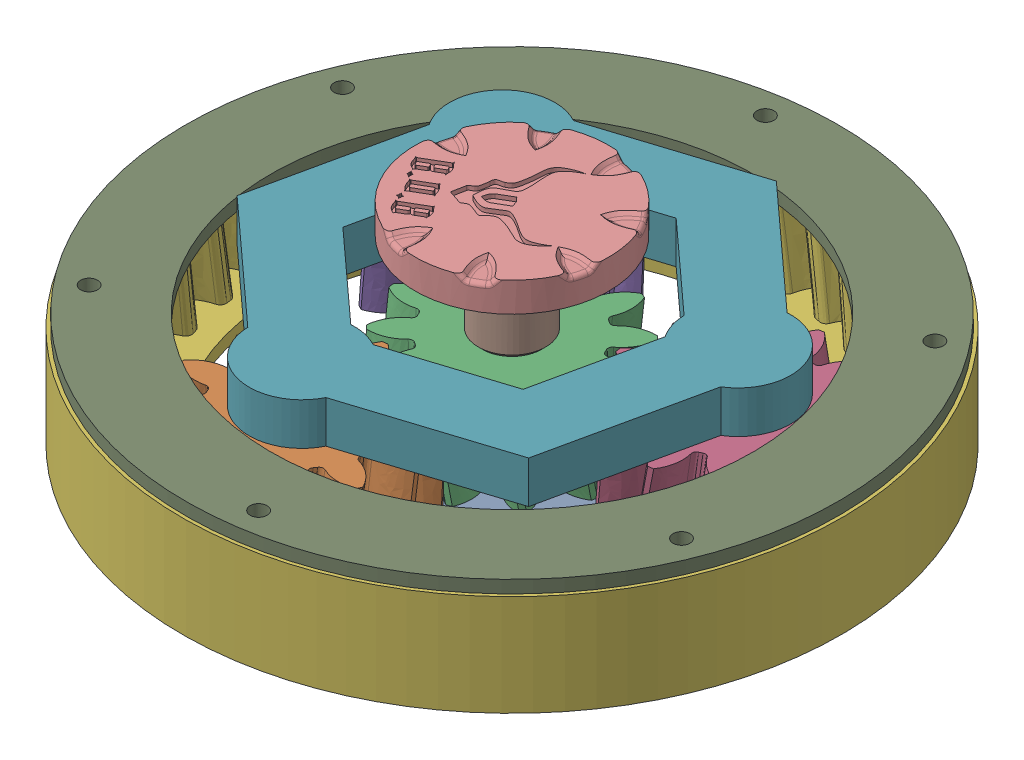
SolidWorks assembly planetary_module_prototype, configuration Default. Lengths in mm.
Overall size (177.94 57 177.94).
10 component instances, 8 part files, 27 mates.
Components (placement in the parent):
- Planet Carrier REV01-1: Planet Carrier REV01 [Default] at (53.0057 38.5104 215.4418) x (-0.977013 0 -0.213181) z (0 1 0) size (94.36 84.54 31)
- planet_helical-1: planet_helical [Default] at (43.976 53.5104 256.8251) x (0.343265 0 0.939239) z (-0.939239 0 0.343265) size (48.42 20.01 48.73)
- sun_helical-1: sun_helical [Default] at (53.0057 53.5104 215.4418) x (0.868502 0 0.495686) z (-0.495686 0 0.868502) size (48.42 20.01 48.73)
- planet_helical-2: planet_helical [Default] at (93.3596 53.5104 202.57) x (0.985013 0 0.172478) z (-0.172478 0 0.985013) size (48.42 20.01 48.73)
- planet_helical-3: planet_helical [Default] at (21.6816 53.5104 186.9302) x (0.641398 0 -0.767208) z (0.767208 0 0.641398) size (48.42 20.01 48.73)
- ring_helical-1: ring_helical [Default] at (53.0057 54.0104 215.4418) x (0.989106 0 -0.147208) z (0.147208 0 0.989106) size (156.59 24 156.59)
- Planet Cap REV01-1: Planet Cap REV01 [Default] at (53.0919 69.5104 215.0469) x (0.673126 0 -0.739528) z (0 1 0) size (98.36 107.21 19)
- Hand Crank Key REV01-1: Hand Crank Key REV01 [Default] at (53.0057 63.5104 215.4418) x (0.495686 0 -0.868502) z (-0.868502 0 -0.495686) size (18.48 32 16)
- ring_helical_cap-1: ring_helical_cap [Default] at (53.0057 64.5104 215.4418) x (0.989106 0 -0.147208) z (0.147208 0 0.989106) size (155 3 155)
- Hand Crank REV01-2: Hand Crank REV01 [Default] at (53.0057 63.5104 215.4418) x (0.504302 0 0.863527) z (0.863527 0 -0.504302) size (46 7 46)
Mates (geometry in assembly coordinates):
- Concentric1: concentric anti-aligned: cylinder of Planet Carrier REV01-1 through (21.6816 64.5104 186.9302) axis (0 -1 0) radius 9.75; cylinder of planet_helical-3 through (21.6816 43.5061 186.9302) axis (0 1 0) radius 10.1
- Coincident1: coincident anti-aligned: plane of Planet Carrier REV01-1 through (53.0057 43.5104 215.4418) normal (0 1 0); plane of planet_helical-3 through (21.6816 43.5104 186.9302) normal (0 -1 0)
- Concentric2: concentric anti-aligned: cylinder of Planet Carrier REV01-1 through (53.0057 84.0165 215.4418) axis (0 -1 0) radius 7.25; cylinder of sun_helical-1 through (53.0057 43.5061 215.4418) axis (0 1 0) radius 7.6
- Coincident2: coincident anti-aligned: plane of Planet Carrier REV01-1 through (53.0057 43.5104 215.4418) normal (0 1 0); plane of sun_helical-1 through (53.0057 43.5104 215.4418) normal (0 -1 0)
- Concentric3: concentric anti-aligned: cylinder of Planet Carrier REV01-1 through (43.976 64.5104 256.8251) axis (0 -1 0) radius 9.75; cylinder of planet_helical-1 through (43.976 43.5061 256.8251) axis (0 1 0) radius 10.1
- Coincident3: coincident anti-aligned: plane of Planet Carrier REV01-1 through (53.0057 43.5104 215.4418) normal (0 1 0); plane of planet_helical-1 through (43.976 43.5104 256.8251) normal (0 -1 0)
- Concentric4: concentric anti-aligned: cylinder of Planet Carrier REV01-1 through (93.3596 64.5104 202.57) axis (0 -1 0) radius 9.75; cylinder of planet_helical-2 through (93.3596 43.5061 202.57) axis (0 1 0) radius 10.1
- Coincident4: coincident anti-aligned: plane of Planet Carrier REV01-1 through (53.0057 43.5104 215.4418) normal (0 1 0); plane of planet_helical-2 through (93.3596 43.5104 202.57) normal (0 -1 0)
- Concentric9: concentric anti-aligned: cylinder of sun_helical-1 through (53.0057 43.5061 215.4418) axis (0 1 0) radius 7.6; cylinder of RING_helical-1 through (53.0057 64.5104 215.4418) axis (0 -1 0) radius 78.2955
- Coincident5: coincident anti-aligned: plane of planet_helical-2 through (93.3596 43.5104 202.57) normal (0 -1 0); plane of RING_helical-1 through (53.0057 43.5104 215.4418) normal (0 1 0)
- Concentric10: concentric anti-aligned: cylinder of sun_helical-1 through (53.0057 43.5061 215.4418) axis (0 1 0) radius 7.6; cylinder of Hand Crank Key REV01-1 through (53.0057 83.5104 215.4418) axis (0 -1 0) radius 8
- Parallel3: parallel anti-aligned: plane of sun_helical-1 through (55.9173 19.1859 220.4273) normal (-0.868502 0 -0.495686); plane of Hand Crank Key REV01-1 through (58.4328 55.5104 215.4148) normal (0.868502 0 0.495686)
- Coincident7: coincident anti-aligned: plane of sun_helical-1 through (53.0057 63.5104 215.4418) normal (0 1 0); plane of Hand Crank Key REV01-1 through (53.0057 63.5104 215.4418) normal (0 -1 0)
- Parallel4: parallel anti-aligned: plane of Planet Carrier REV01-1 through (48.2457 54.5104 260.7114) normal (-0.977013 0 -0.213181); plane of Planet Cap REV01-1 through (49.1776 55.5104 254.7986) normal (0.977013 0 0.213181)
- Coincident9: coincident anti-aligned: plane of Planet Carrier REV01-1 through (98.8601 54.5104 200.8155) normal (-0.673126 0 0.739528); plane of Planet Cap REV01-1 through (94.5904 55.5104 196.9292) normal (0.673126 0 -0.739528)
- Coincident10: coincident anti-aligned: plane of Planet Carrier REV01-1 through (22.9124 54.5104 181.2894) normal (0.303887 0 0.952708); plane of Planet Cap REV01-1 through (17.7969 55.5104 182.921) normal (-0.303887 0 -0.952708)
- Coincident11: coincident anti-aligned: plane of Planet Carrier REV01-1 through (21.6816 64.5104 186.9302) normal (0 1 0); plane of Planet Cap REV01-1 through (53.0919 64.5104 215.0469) normal (0 -1 0)
- Concentric14: concentric anti-aligned: cylinder of RING_helical-1 through (-2.9778 44.5104 259.9175) axis (0 1 0) radius 2; cylinder of ring_helical_cap-1 through (-2.9778 67.5104 259.9175) axis (0 -1 0) radius 2
- Concentric15: concentric anti-aligned: cylinder of RING_helical-1 through (108.9893 44.5104 170.966) axis (0 1 0) radius 2; cylinder of ring_helical_cap-1 through (108.9893 67.5104 170.966) axis (0 -1 0) radius 2
- Coincident14: coincident anti-aligned: plane of RING_helical-1 through (53.0057 64.5104 215.4418) normal (0 1 0); plane of ring_helical_cap-1 through (53.0057 64.5104 215.4418) normal (0 -1 0)
- Concentric16: concentric aligned: cylinder of Hand Crank Key REV01-1 through (53.0057 83.5104 215.4418) axis (0 -1 0) radius 8; cylinder of Hand Crank REV01-2 through (53.0057 90.5104 215.4418) axis (0 -1 0) radius 23
- Parallel7: parallel anti-aligned: plane of Hand Crank Key REV01-1 through (57.6643 87.5104 223.4187) normal (0.868502 0 0.495686); plane of Hand Crank REV01-2 through (62.5896 87.5104 215.3941) normal (-0.868502 0 -0.495686)
- Coincident17: coincident anti-aligned: plane of Hand Crank Key REV01-1 through (53.0057 87.5104 215.4418) normal (0 1 0); plane of Hand Crank REV01-2 through (53.0057 87.5104 215.4418) normal (0 -1 0)
- GearMate1: gear = 12 : 12 mm: cylinder of planet_helical-2 through (93.3596 43.5061 202.57) axis (0 1 0) radius 10.1; cylinder of sun_helical-1 through (53.0057 43.5061 215.4418) axis (0 1 0) radius 7.6
- GearMate2: gear = 12 : 12 mm: cylinder of planet_helical-1 through (43.976 43.5061 256.8251) axis (0 1 0) radius 10.1; cylinder of sun_helical-1 through (53.0057 43.5061 215.4418) axis (0 1 0) radius 7.6
- GearMate3: gear = 12 : 12 mm: cylinder of sun_helical-1 through (53.0057 43.5061 215.4418) axis (0 1 0) radius 7.6; cylinder of planet_helical-3 through (21.6816 43.5061 186.9302) axis (0 1 0) radius 10.1
- GearMate4: gear = 36 : 12 mm: cylinder of planet_helical-1 through (43.976 43.5061 256.8251) axis (0 1 0) radius 10.1; cylinder of RING_helical-1 through (53.0057 64.5104 215.4418) axis (0 -1 0) radius 78.2955
